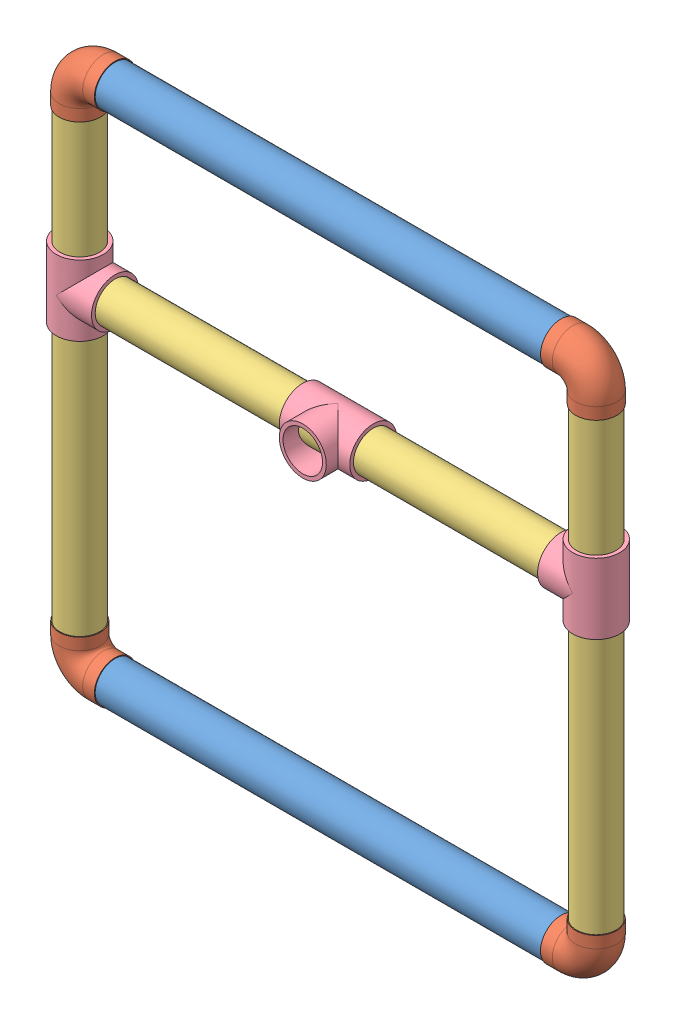
SolidWorks assembly Assem1, configuration Default. Lengths in mm.
Overall size (304.8 301.63 38.88).
12 component instances, 4 part files, 26 mates.
Components (placement in the parent):
- PVC_tube_12in-1: PVC_tube_12in [Default] at (224.9643 139.1096 188.8412) size (254 21.34 21.34)
- PVC_90-1: PVC_90 [Default] at (-23.4538 156.2418 188.8412) x (1 0 0) z (0 0 1) size (30.16 30.16 22.23)
- PVC_90-2: PVC_90 [Default] at (220.532 157.3915 188.8412) x (0 1 0) z (0 0 1) size (30.16 30.16 22.23)
- PVC_tube_10in-1: PVC_tube_10in [Default] at (237.6643 151.8096 188.8412) x (0 -1 0) z (0 0 1) size (254 21.34 21.34)
- PVC_90-3: PVC_90 [Default] at (219.3823 401.3774 188.8412) x (-1 0 0) z (0 0 1) size (30.16 30.16 22.23)
- PVC_tube_12in-2: PVC_tube_12in [Default] at (224.9643 418.5096 188.8412) x (1 0 0) z (0 0 1) size (254 21.34 21.34)
- PVC_90-4: PVC_90 [Default] at (-24.6035 400.2277 188.8412) x (0 -1 0) z (0 0 1) size (30.16 30.16 22.23)
- PVC_tube_10in-2: PVC_tube_10in [Default] at (-41.7357 405.8096 188.8412) x (0 1 0) z (-0.97697 0 0.213378) size (254 21.34 21.34)
- PVC_tee-1: PVC_tee [Default] at (-41.7357 316.9096 188.8412) x (0 -1 0) z (0 0 1) size (38.1 38.88 25.4)
- PVC_tee-2: PVC_tee [Default] at (237.6643 316.9096 188.8412) x (0 1 0) z (0 0 1) size (38.1 38.88 25.4)
- PVC_tube_10in-3: PVC_tube_10in [Default] at (224.9643 316.9096 188.8412) size (254 21.34 21.34)
- PVC_tee-3: PVC_tee [Default] at (97.9643 316.9096 188.8412) x (1 0 0) z (0 -1 0) size (38.1 38.88 25.4)
Mates (geometry in assembly coordinates):
- Concentric4: concentric: cylinder of PVC_tube_12in-1 through (-29.0357 139.1096 188.8412) axis (1 0 0) radius 10.668; cylinder of PVC_90-1 through (-29.0357 139.1096 188.8412) axis (1 0 0) radius 10.6807
- Distance2: distance = 6.35 mm: plane of PVC_90-1 through (-22.6857 139.1096 188.8412) normal (1 0 0); plane of PVC_tube_12in-1 through (-29.0357 139.1096 188.8412) normal (-1 0 0)
- Distance3: distance = 6.35 mm anti-aligned: plane of PVC_tube_12in-1 through (224.9643 139.1096 188.8412) normal (1 0 0); plane of PVC_90-2 through (218.6143 139.1096 188.8412) normal (-1 0 0)
- Concentric11: concentric: circle of PVC_tube_12in-1; circle of PVC_90-2
- Distance4: distance = 6.35 mm: plane of PVC_90-2 through (237.6643 158.1596 188.8412) normal (0 1 0); plane of PVC_tube_10in-1 through (237.6643 151.8096 188.8412) normal (0 -1 0)
- Concentric13: concentric: circle of PVC_90-2; circle of PVC_tube_10in-1
- Concentric18: concentric: circle of PVC_tube_10in-1; circle of PVC_90-3
- Distance6: distance = 6.35 mm: plane of PVC_90-3 through (237.6643 399.4596 188.8412) normal (0 -1 0); plane of PVC_tube_10in-1 through (237.6643 405.8096 188.8412) normal (0 1 0)
- Distance7: distance = 6.35 mm: plane of PVC_90-3 through (218.6143 418.5096 188.8412) normal (-1 0 0); plane of PVC_tube_12in-2 through (224.9643 418.5096 188.8412) normal (1 0 0)
- Concentric19: concentric: circle of PVC_90-3; circle of PVC_tube_12in-2
- Distance8: distance = 6.35 mm: plane of PVC_90-4 through (-22.6857 418.5096 188.8412) normal (1 0 0); plane of PVC_tube_12in-2 through (-29.0357 418.5096 188.8412) normal (-1 0 0)
- Concentric20: concentric: circle of PVC_tube_12in-2; circle of PVC_90-4
- Distance9: distance = 6.35 mm: plane of PVC_tube_10in-2 through (-41.7357 405.8096 188.8412) normal (0 1 0); plane of PVC_90-4 through (-41.7357 399.4596 188.8412) normal (0 -1 0)
- Concentric21: concentric: circle of PVC_90-4; circle of PVC_tube_10in-2
- Concentric22: concentric: cylinder of PVC_tube_10in-2 through (-41.7357 151.8096 188.8412) axis (0 1 0) radius 10.668; cylinder of PVC_tee-1 through (-41.7357 335.9596 188.8412) axis (0 -1 0) radius 10.6807
- Parallel13: parallel: plane of PVC_90-1 through (-41.7357 158.1596 188.8412) normal (0 1 0); plane of PVC_tube_10in-2 through (-41.7357 151.8096 188.8412) normal (0 -1 0)
- Distance11: distance = 63.5 mm: plane of PVC_90-4 through (-41.7357 399.4596 188.8412) normal (0 -1 0); plane of PVC_tee-1 through (-41.7357 335.9596 188.8412) normal (0 1 0)
- Concentric23: concentric: cylinder of PVC_tube_10in-1 through (237.6643 405.8096 188.8412) axis (0 -1 0) radius 10.668; cylinder of PVC_tee-2 through (237.6643 297.8596 188.8412) axis (0 1 0) radius 10.6807
- Distance12: distance = 63.5 mm: plane of PVC_90-3 through (237.6643 399.4596 188.8412) normal (0 -1 0); plane of PVC_tee-2 through (237.6643 335.9596 188.8412) normal (0 1 0)
- Parallel14: parallel: line of PVC_tee-2 through (237.6643 316.9096 188.8412) axis (-1 0 0); line of assembly
- Coincident2: coincident: line of PVC_tee-1 through (-41.7357 316.9096 188.8412) axis (1 0 0); line of assembly
- Concentric24: concentric: cylinder of PVC_tee-2 through (250.3653 316.9096 188.8412) axis (-1 0 0) radius 10.6807; cylinder of PVC_tube_10in-3 through (-29.0357 316.9096 188.8412) axis (1 0 0) radius 10.668
- Distance13: distance = 6.35 mm anti-aligned: plane of PVC_tube_10in-3 through (224.9643 316.9096 188.8412) normal (1 0 0); plane of PVC_tee-2 through (218.6143 316.9096 188.8412) normal (-1 0 0)
- Concentric25: concentric: cylinder of PVC_tube_10in-3 through (-29.0357 316.9096 188.8412) axis (1 0 0) radius 10.668; cylinder of PVC_tee-3 through (78.9143 316.9096 188.8412) axis (1 0 0) radius 10.6807
- Coincident5: coincident: point of PVC_tee-3; point of assembly
- Perpendicular1: perpendicular: line of PVC_tee-3 through (97.9643 316.9096 188.8412) axis (0 0 1); line of assembly
